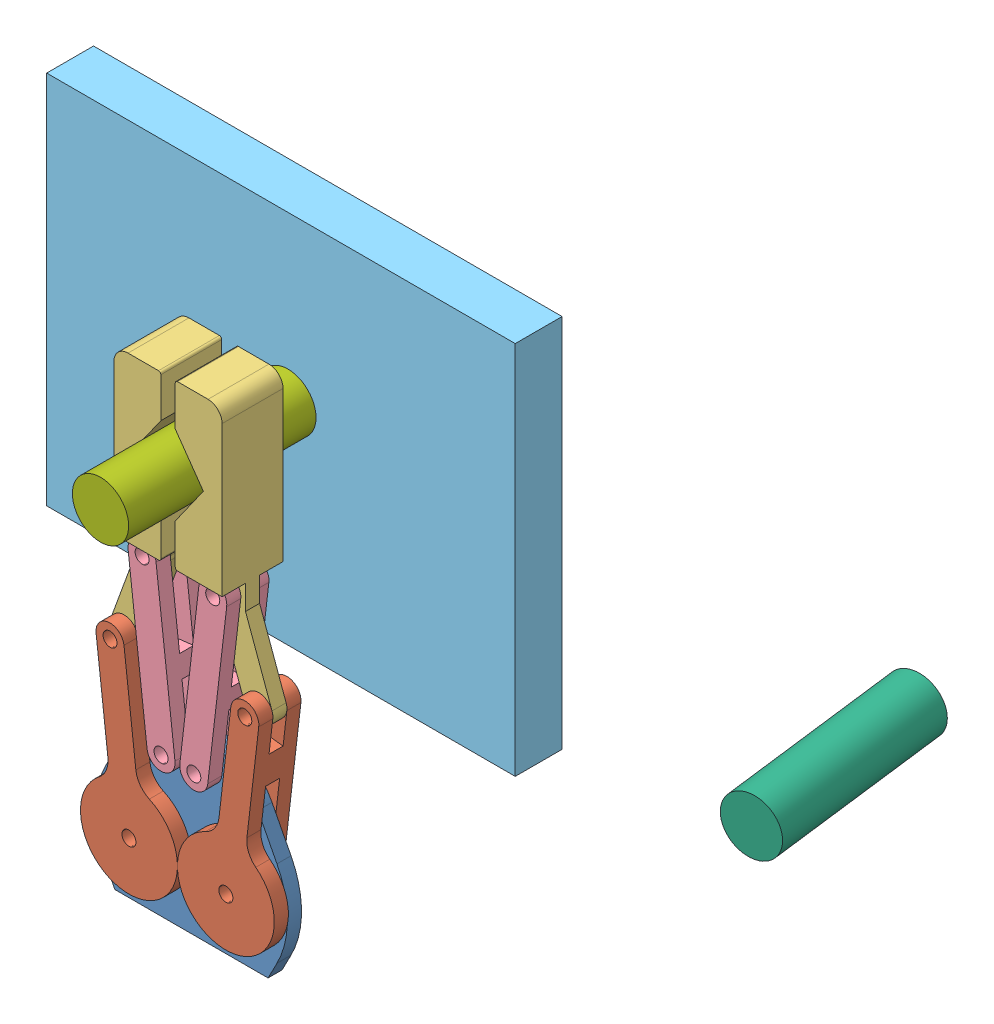
SolidWorks assembly Assieme2, configuration Default. Lengths in mm.
Overall size (154.43 122.47 85.05).
10 component instances, 7 part files, 11 mates.
Components (placement in the parent):
- Base-1: Base [Default] at (1.4587 -10.9861 39.4684) size (40.97 38 3)
- Link 1-1: Link 1 [Default] at (1.4587 -10.9861 40.9684) x (0.115407 0.993318 0) z (0 0 1) size (48.34 20.68 9)
- Link 2 Front-1: Link 2 Front [Default] at (5.4979 23.78 40.9684) size (15.84 59.79 13)
- Link 3-1: Link 3 [Default] at (-5.3817 7.8077 36.4684) x (0.993318 -0.115407 0) z (0 0 1) size (6 41 9)
- Link 1-2: Link 1 [Default] at (-19.2221 -10.9861 40.9684) x (-0.115407 0.993318 0) z (0 0 1) size (48.34 20.68 9)
- Link 3-2: Link 3 [Default] at (-12.3817 7.8077 36.4684) x (0.993318 0.115407 0) z (0 0 1) size (6 41 9)
- Link 2 Front-2: Link 2 Front [Default] at (-23.2614 23.78 40.9684) x (-1 0 0) z (0 0 -1) size (15.84 59.79 13)
- Piano_ProvaContatto-1: Piano_ProvaContatto [Default] at (-60.9456 17.4856 21.3055) x (1 0 0) z (0 1 0) size (100 10 80)
- Parte1^Assieme2-1: Parte1^Assieme2 [Default] at (85.5985 29.6493 17.4385) x (-0.114345 0.012045 -0.993368) z (0.905542 -0.409961 -0.109207) size (40 12 12) (virtual)
- Oggetto cilindrico-3: Oggetto cilindrico [Default] at (-8.8817 57.096 61.8801) x (0 0 -1) z (1 0 0) size (40 12 12)
Mates (geometry in assembly coordinates):
- Coincidente8: coincident aligned: circle of Base-1; circle of Link 1-1
- Coincidente9: coincident aligned: circle of Link 1-1; circle of Link 2 Front-1
- Coincidente10: coincident aligned: circle of Link 2 Front-1; circle of Link 3-1
- Coincidente11: coincident anti-aligned: circle of Base-1; circle of Link 3-1
- Coincidente12: coincident aligned: circle of Base-1; circle of Link 1-2
- Coincidente13: coincident anti-aligned: circle of Link 1-2; circle of Link 2 Front-2
- Coincidente14: coincident anti-aligned: circle of Link 3-2; circle of Link 2 Front-2
- Coincidente15: coincident aligned: circle of Base-1; circle of Link 3-2
- AccoppiaIngranaggi4: gear = 20.68 : 20.68 mm: cylinder of Link 1-1 through (1.4587 -10.9861 36.4684) axis (0 0 1) radius 10.34; cylinder of Link 1-2 through (-19.2221 -10.9861 36.4684) axis (0 0 1) radius 10.34
- Parallelo5: parallel anti-aligned: plane of Piano_ProvaContatto-1 through (-60.9456 17.4856 21.3055) normal (0 0 1); plane of Oggetto cilindrico-3 through (-8.8817 57.096 21.8801) normal (0 0 -1)
- Coincidente28: coincident anti-aligned: plane of Piano_ProvaContatto-1 through (-60.9456 17.4856 21.3055) normal (0 0 1); plane of Oggetto cilindrico-3 through (-8.8817 57.096 21.8801) normal (0 0 -1)
